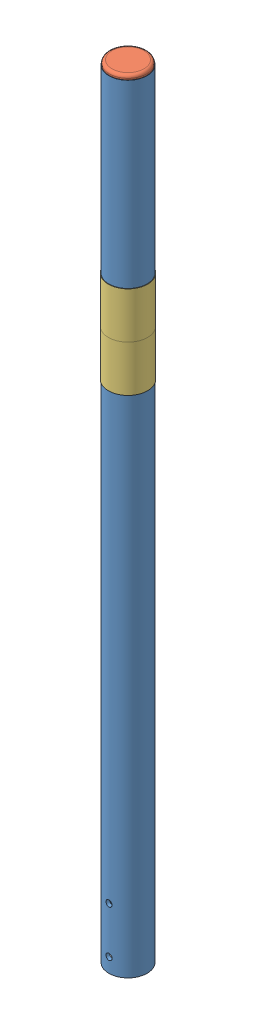
SolidWorks assembly TE-23036, configuration Default. Lengths in mm.
Overall size (43.32 860.42 43.32).
4 component instances, 3 part files, 6 mates.
Components (placement in the parent):
- TE-23016-1: TE-23016 [Default] at (508.9704 148.3 759.3724) size (42.16 855.66 42.16)
- CCF-RT-13-1-1: CCF-RT-13-1 [Default] at (508.9704 991.2625 759.3724) x (0.998713 0 0.050715) z (-0.050715 0 0.998713) size (41.27 17.46 41.27)
- tape_VISIONTARGET-1: tape_VISIONTARGET [Default] at (508.9704 754.725 759.3724) size (43.18 50.8 43.18)
- tape_VISIONTARGET-2: tape_VISIONTARGET [Default] at (508.9704 703.925 759.3724) size (43.18 50.8 43.18)
Mates (geometry in assembly coordinates):
- Concentric1: concentric aligned: cylinder of TE-23035-1 through (508.9704 1003.9625 759.3724) axis (0 -1 0) radius 21.082; cylinder of CCF-RT-13-1-1 through (508.9704 991.2625 759.3724) axis (0 -1 0) radius 20.6375
- Coincident1: coincident anti-aligned: plane of TE-23035-1 through (508.9704 1003.9625 759.3724) normal (0 1 0); plane of CCF-RT-13-1-1 through (524.8249 1003.9625 760.1775) normal (0 -1 0)
- Concentric2: concentric aligned: cylinder of TE-23035-1 through (508.9704 1003.9625 759.3724) axis (0 -1 0) radius 21.082; cylinder of tape_VISIONTARGET-1 through (508.9704 805.525 759.3724) axis (0 -1 0) radius 21.59
- Concentric3: concentric aligned: cylinder of TE-23035-1 through (508.9704 1003.9625 759.3724) axis (0 -1 0) radius 21.082; cylinder of tape_VISIONTARGET-2 through (508.9704 754.725 759.3724) axis (0 -1 0) radius 21.59
- Distance1: distance = 203.2 mm aligned: plane of tape_VISIONTARGET-1 through (508.9704 805.525 759.3724) normal (0 1 0); plane of CCF-RT-13-1-1 through (529.5813 1008.725 760.419) normal (0 1 0)
- Coincident3: coincident anti-aligned: plane of tape_VISIONTARGET-1 through (508.9704 754.725 759.3724) normal (0 -1 0); plane of tape_VISIONTARGET-2 through (508.9704 754.725 759.3724) normal (0 1 0)
